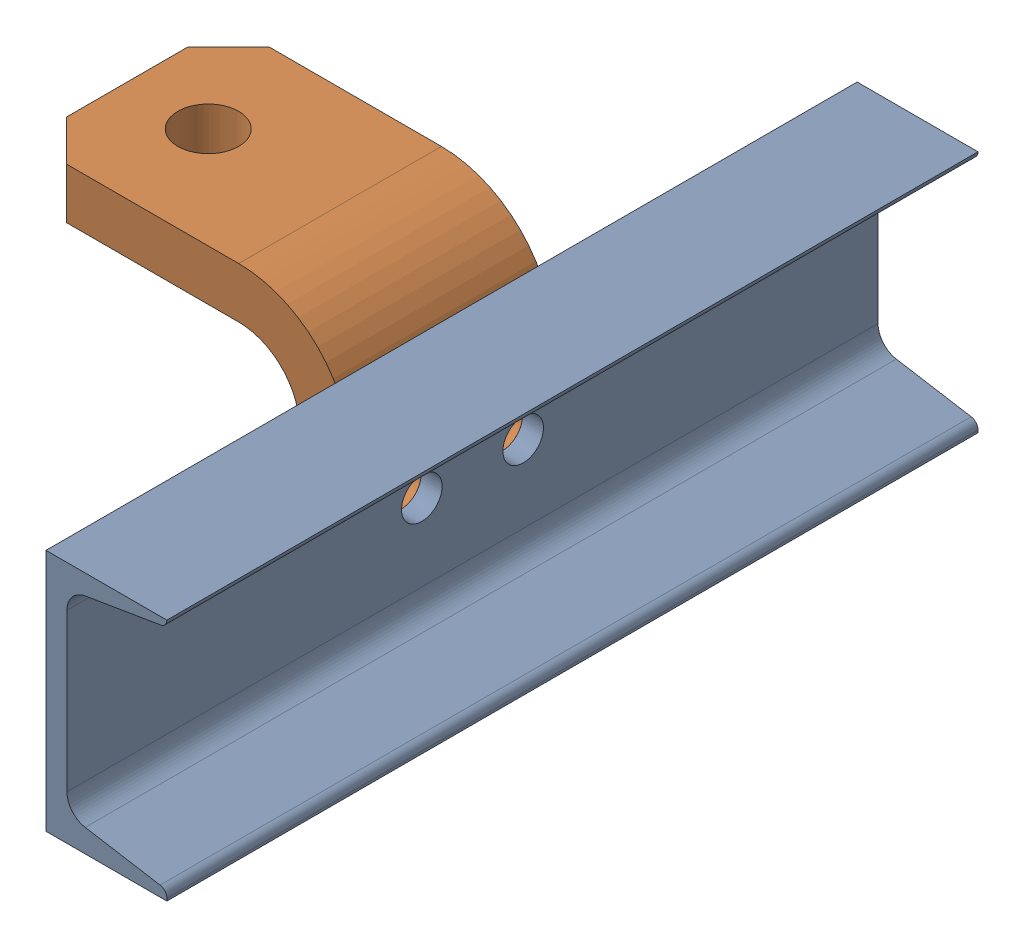
SolidWorks assembly Quiz 6, configuration Default. Lengths in mm.
Overall size (139.45 88.9 254).
2 component instances, 2 part files, 3 mates.
Components (placement in the parent):
- Hitch Channel 7-3-1: Hitch Channel 7-3 [Default] at origin size (37.85 76.2 254)
- Hitch 7-3-1: Hitch 7-3 [Default] at (-76.2 34.925 0) x (-1 0 0) z (0 0 -1) size (101.6 76.2 63.5)
Mates (geometry in assembly coordinates):
- Coincident1: coincident anti-aligned: plane of Hitch Channel 7-3-1 through (0 -38.1 127) normal (-1 0 0); plane of Hitch 7-3-1 through (0 -25.4 -31.75) normal (1 0 0)
- Coincident2: coincident aligned: line of Hitch Channel 7-3-1 through (6.5532 0 15.875) axis (-1 0 0); line of Hitch 7-3-1 through (0 0 15.875) axis (-1 0 0)
- Coincident3: coincident aligned: line of Hitch Channel 7-3-1 through (6.5532 0 -15.875) axis (-1 0 0); line of Hitch 7-3-1 through (0 0 -15.875) axis (-1 0 0)
